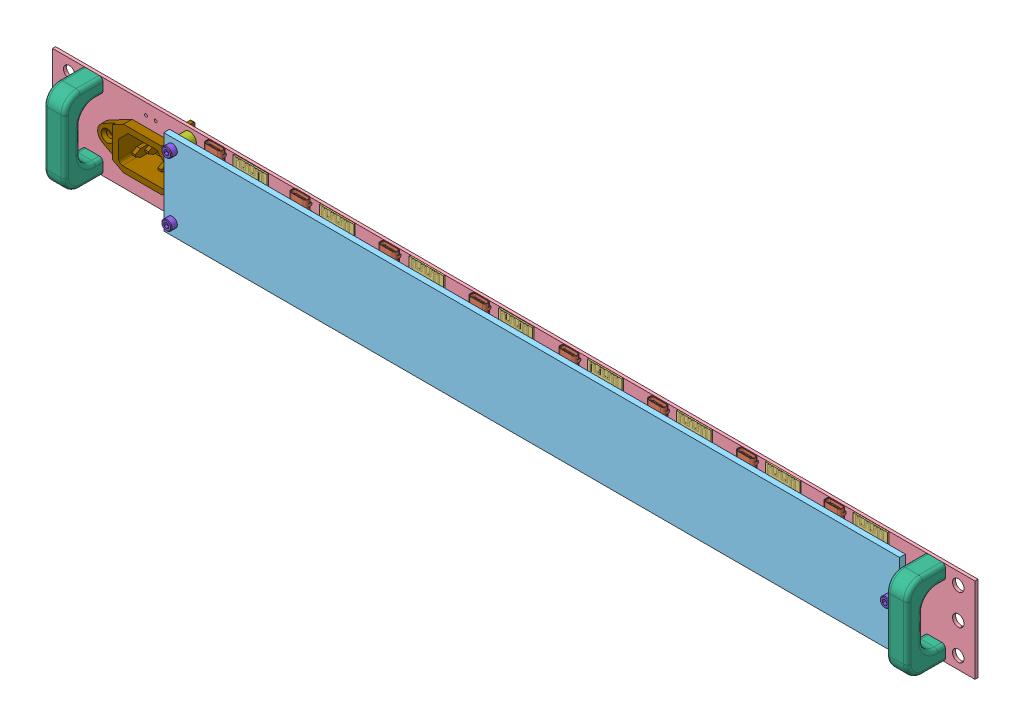
SolidWorks assembly RACK-ESP32S-SOLID, configuration Défaut. Lengths in mm.
Overall size (482.6 44.77 41.9).
68 component instances, 10 part files, 45 mates.
Components (placement in the parent):
- RACK-ESP32S-SOLID.step-1: RACK-ESP32S-SOLID.step [Défaut] at origin size (482.6 44.77 11.2)
  - OLED 128x32 Display.step-1: OLED 128x32 Display.step [Défaut] at (348.1175 -118.745 4.15) size (38 12 11.2)
    - COMPOUND.step-1: COMPOUND.step [Défaut] at origin size (38 12 11.2)
  - USB Type C Port (SMD Type).step-1: USB Type C Port (SMD Type).step [Défaut] at (304.165 -83.395 3.15) x (-1 0 0) z (0 0 -1) size (8.94 7.9 4.2)
    - COMPOUND-0.step-1: COMPOUND-0.step [Défaut] at origin size (8.94 7.9 4.2)
  - ESP32-S3-WROOM-1.step-1: ESP32-S3-WROOM-1.step [Défaut] at (406.16 -101.43 1.65) size (18 25.5 3.1)
    - COMPOUND-1.step-1: COMPOUND-1.step [Défaut] at origin size (18 25.5 3.1)
  - USB Type C Port (SMD Type).step-2: USB Type C Port (SMD Type).step [Défaut] at (397.129 -83.395 3.15) x (-1 0 0) z (0 0 -1) size (8.94 7.9 4.2)
    - COMPOUND-0.step-1: COMPOUND-0.step [Défaut] at origin size (8.94 7.9 4.2)
  - USB Type C Port (SMD Type).step-3: USB Type C Port (SMD Type).step [Défaut] at (350.52 -83.515 3.15) x (-1 0 0) z (0 0 -1) size (8.94 7.9 4.2)
    - COMPOUND-0.step-1: COMPOUND-0.step [Défaut] at origin size (8.94 7.9 4.2)
  - OLED 128x32 Display.step-2: OLED 128x32 Display.step [Défaut] at (440.8275 -118.745 4.15) size (38 12 11.2)
    - COMPOUND.step-1: COMPOUND.step [Défaut] at origin size (38 12 11.2)
  - OLED 128x32 Display.step-3: OLED 128x32 Display.step [Défaut] at (207.1475 -118.745 4.15) size (38 12 11.2)
    - COMPOUND.step-1: COMPOUND.step [Défaut] at origin size (38 12 11.2)
  - ESP32-S3-WROOM-1.step-2: ESP32-S3-WROOM-1.step [Défaut] at (359.745 -101.527 1.65) size (18 25.5 3.1)
    - COMPOUND-1.step-1: COMPOUND-1.step [Défaut] at origin size (18 25.5 3.1)
  - OLED 128x32 Display.step-4: OLED 128x32 Display.step [Défaut] at (254.7725 -118.745 4.15) size (38 12 11.2)
    - COMPOUND.step-1: COMPOUND.step [Défaut] at origin size (38 12 11.2)
  - ESP32-S3-WROOM-1.step-3: ESP32-S3-WROOM-1.step [Défaut] at (266.4 -101.745 1.65) size (18 25.5 3.1)
    - COMPOUND-1.step-1: COMPOUND-1.step [Défaut] at origin size (18 25.5 3.1)
  - ESP32-S3-WROOM-1.step-4: ESP32-S3-WROOM-1.step [Défaut] at (127.535 -101.748 1.65) size (18 25.5 3.1)
    - COMPOUND-1.step-1: COMPOUND-1.step [Défaut] at origin size (18 25.5 3.1)
  - USB Type C Port (SMD Type).step-4: USB Type C Port (SMD Type).step [Défaut] at (163.425 -83.145 3.15) x (-1 0 0) z (0 0 -1) size (8.94 7.9 4.2)
    - COMPOUND-0.step-1: COMPOUND-0.step [Défaut] at origin size (8.94 7.9 4.2)
  - OLED 128x32 Display.step-5: OLED 128x32 Display.step [Défaut] at (114.3 -118.745 4.15) size (38 12 11.2)
    - COMPOUND.step-1: COMPOUND.step [Défaut] at origin size (38 12 11.2)
  - USB Type C Port (SMD Type).step-5: USB Type C Port (SMD Type).step [Défaut] at (118.745 -83.268 3.15) x (-1 0 0) z (0 0 -1) size (8.94 7.9 4.2)
    - COMPOUND-0.step-1: COMPOUND-0.step [Défaut] at origin size (8.94 7.9 4.2)
  - ESP32-S3-WROOM-1.step-5: ESP32-S3-WROOM-1.step [Défaut] at (172.81 -101.595 1.65) size (18 25.5 3.1)
    - COMPOUND-1.step-1: COMPOUND-1.step [Défaut] at origin size (18 25.5 3.1)
  - ESP32-S3-WROOM-1.step-6: ESP32-S3-WROOM-1.step [Défaut] at (313.08 -101.525 1.65) size (18 25.5 3.1)
    - COMPOUND-1.step-1: COMPOUND-1.step [Défaut] at origin size (18 25.5 3.1)
  - USB Type C Port (SMD Type).step-6: USB Type C Port (SMD Type).step [Défaut] at (442.976 -83.395 3.15) x (-1 0 0) z (0 0 -1) size (8.94 7.9 4.2)
    - COMPOUND-0.step-1: COMPOUND-0.step [Défaut] at origin size (8.94 7.9 4.2)
  - USB Type C Port (SMD Type).step-7: USB Type C Port (SMD Type).step [Défaut] at (257.175 -83.295 3.15) x (-1 0 0) z (0 0 -1) size (8.94 7.9 4.2)
    - COMPOUND-0.step-1: COMPOUND-0.step [Défaut] at origin size (8.94 7.9 4.2)
  - ESP32-S3-WROOM-1.step-7: ESP32-S3-WROOM-1.step [Défaut] at (452.115 -101.595 1.65) size (18 25.5 3.1)
    - COMPOUND-1.step-1: COMPOUND-1.step [Défaut] at origin size (18 25.5 3.1)
  - ESP32-S3-WROOM-1.step-8: ESP32-S3-WROOM-1.step [Défaut] at (219.8 -101.455 1.65) size (18 25.5 3.1)
    - COMPOUND-1.step-1: COMPOUND-1.step [Défaut] at origin size (18 25.5 3.1)
  - USB Type C Port (SMD Type).step-8: USB Type C Port (SMD Type).step [Défaut] at (210.05 -83.325 3.15) x (-1 0 0) z (0 0 -1) size (8.94 7.9 4.2)
    - COMPOUND-0.step-1: COMPOUND-0.step [Défaut] at origin size (8.94 7.9 4.2)
  - OLED 128x32 Display.step-6: OLED 128x32 Display.step [Défaut] at (160.655 -118.745 4.15) size (38 12 11.2)
    - COMPOUND.step-1: COMPOUND.step [Défaut] at origin size (38 12 11.2)
  - OLED 128x32 Display.step-7: OLED 128x32 Display.step [Défaut] at (301.1275 -118.745 4.15) size (38 12 11.2)
    - COMPOUND.step-1: COMPOUND.step [Défaut] at origin size (38 12 11.2)
  - OLED 128x32 Display.step-8: OLED 128x32 Display.step [Défaut] at (394.4725 -118.745 4.15) size (38 12 11.2)
    - COMPOUND.step-1: COMPOUND.step [Défaut] at origin size (38 12 11.2)
  - RACK-ESP32S3 PCB.step-1: RACK-ESP32S3 PCB.step [Défaut] at origin size (482.6 44.6 1.6)
- vitre-1: vitre [Défaut] at (292.1466 -98.3103 7.65) size (385 44.6 3)
- poignee-1: poignee [Défaut] at (53.281 -98.2603 1.6) size (11 44.5 20)
- poignee-2: poignee [Défaut] at (494.089 -98.2603 1.6) size (11 44.5 20)
- spacers-1: spacers [Défaut] at (104.14 -114.3 1.6) size (7 7 6.05)
- spacers-2: spacers [Défaut] at (104.14 -81.28 1.6) size (7 7 6.05)
- spacers-3: spacers [Défaut] at (480.06 -97.155 1.6) size (7 7 6.05)
- socket head cap screw_ai-1: socket head cap screw_ai [HX-SHCS 0.125-44x0.188x0.188-N] at (104.14 -81.28 13.825) x (0 0 -1) z (1 0 0) size (7.95 5.21 5.21)
- socket head cap screw_ai-2: socket head cap screw_ai [HX-SHCS 0.125-44x0.188x0.188-N] at (104.14 -114.3 13.825) x (0 0 -1) z (1 0 0) size (7.95 5.21 5.21)
- socket head cap screw_ai-3: socket head cap screw_ai [HX-SHCS 0.125-44x0.188x0.188-N] at (480.06 -97.155 13.825) x (0 0 -1) z (1 0 0) size (7.95 5.21 5.21)
- IEC-C4-3pins-1: IEC-C4-3pins [Default] at (83.9847 -98.3103 4.6) size (50 22 26.4)
- oleddisplay-1: oleddisplay [Défaut] at (134.3 -112.795 6.65) size (26 11.6 0.1)
- oleddisplay-2: oleddisplay [Défaut] at (180.655 -112.795 6.65) size (26 11.6 0.1)
- oleddisplay-3: oleddisplay [Défaut] at (227.1475 -112.795 6.65) size (26 11.6 0.1)
- oleddisplay-4: oleddisplay [Défaut] at (274.7725 -112.795 6.65) size (26 11.6 0.1)
- oleddisplay-5: oleddisplay [Défaut] at (321.1275 -112.795 6.65) size (26 11.6 0.1)
- oleddisplay-6: oleddisplay [Défaut] at (368.1175 -112.795 6.65) size (26 11.6 0.1)
- oleddisplay-7: oleddisplay [Défaut] at (414.4725 -112.795 6.65) size (26 11.6 0.1)
- oleddisplay-8: oleddisplay [Défaut] at (460.8275 -112.795 6.65) size (26 11.6 0.1)
Mates (geometry in assembly coordinates):
- Coïncidente2: coincident aligned: plane of RACK-ESP32S-SOLID.step-1/RACK-ESP32S3 PCB.step-1 through (514.985 -120.6103 0) normal (0 -1 0); plane of vitre-1 through (99.6466 -120.6103 10.65) normal (0 -1 0)
- Coïncidente4: coincident anti-aligned: plane of vitre-1 through (292.1466 -98.3103 7.65) normal (0 0 -1)
- Coaxiale1: concentric aligned: cylinder of RACK-ESP32S-SOLID.step-1/RACK-ESP32S3 PCB.step-1 through (480.06 -97.155 -0.8) axis (0 0 1) radius 1.75; cylinder of vitre-1 through (480.06 -97.155 0.65) axis (0 0 1) radius 1.75
- Coïncidente5: coincident anti-aligned: plane of RACK-ESP32S-SOLID.step-1/RACK-ESP32S3 PCB.step-1 through (273.685 -98.3103 1.6) normal (0 0 1); plane of poignee-1 through (53.281 -98.2603 1.6) normal (0 0 -1)
- Coaxiale2: concentric anti-aligned: circle of RACK-ESP32S-SOLID.step-1/RACK-ESP32S3 PCB.step-1; circle of poignee-1
- Coïncidente7: coincident anti-aligned: plane of RACK-ESP32S-SOLID.step-1/RACK-ESP32S3 PCB.step-1 through (273.685 -98.3103 1.6) normal (0 0 1); plane of poignee-2 through (494.089 -98.2603 1.6) normal (0 0 -1)
- Coaxiale3: concentric anti-aligned: circle of RACK-ESP32S-SOLID.step-1/RACK-ESP32S3 PCB.step-1; circle of poignee-2
- Coïncidente9: coincident anti-aligned: plane of RACK-ESP32S-SOLID.step-1/RACK-ESP32S3 PCB.step-1 through (273.685 -98.3103 1.6) normal (0 0 1); plane of spacers-1 through (104.14 -114.3 1.6) normal (0 0 -1)
- Coaxiale4: concentric anti-aligned: cylinder of RACK-ESP32S-SOLID.step-1/RACK-ESP32S3 PCB.step-1 through (104.14 -114.3 -0.8) axis (0 0 1) radius 1.75; cylinder of spacers-1 through (104.14 -114.3 17.5495) axis (0 0 -1) radius 1.75
- Coïncidente10: coincident anti-aligned: plane of RACK-ESP32S-SOLID.step-1/RACK-ESP32S3 PCB.step-1 through (273.685 -98.3103 1.6) normal (0 0 1); plane of spacers-2 through (104.14 -81.28 1.6) normal (0 0 -1)
- Coïncidente11: coincident anti-aligned: circle of vitre-1; cylinder of spacers-2 through (104.14 -81.28 17.5495) axis (0 0 -1) radius 1.75
- Coïncidente12: coincident anti-aligned: plane of RACK-ESP32S-SOLID.step-1/RACK-ESP32S3 PCB.step-1 through (273.685 -98.3103 1.6) normal (0 0 1); plane of spacers-3 through (480.06 -97.155 1.6) normal (0 0 -1)
- Coaxiale5: concentric anti-aligned: circle of RACK-ESP32S-SOLID.step-1/RACK-ESP32S3 PCB.step-1; circle of spacers-3
- Coaxiale61: concentric aligned: cylinder of vitre-1 through (104.14 -81.28 0.65) axis (0 0 1) radius 1.75; cylinder of socket head cap screw_ai-1 through (104.14 -81.28 45.575) axis (0 0 1) radius 1.5875
- Coïncidente141: coincident anti-aligned: plane of vitre-1 through (292.1466 -98.3103 10.65) normal (0 0 1); plane of socket head cap screw_ai-1 through (104.14 -78.6765 10.65) normal (0 0 -1)
- Coaxiale71: concentric aligned: cylinder of vitre-1 through (104.14 -114.3 0.65) axis (0 0 1) radius 1.75; cylinder of socket head cap screw_ai-2 through (104.14 -114.3 45.575) axis (0 0 1) radius 1.5875
- Coïncidente151: coincident anti-aligned: plane of vitre-1 through (292.1466 -98.3103 10.65) normal (0 0 1); plane of socket head cap screw_ai-2 through (104.14 -111.6965 10.65) normal (0 0 -1)
- Coaxiale81: concentric aligned: cylinder of vitre-1 through (480.06 -97.155 0.65) axis (0 0 1) radius 1.75; cylinder of socket head cap screw_ai-3 through (480.06 -97.155 45.575) axis (0 0 1) radius 1.5875
- Coïncidente161: coincident anti-aligned: plane of vitre-1 through (292.1466 -98.3103 10.65) normal (0 0 1); plane of socket head cap screw_ai-3 through (480.06 -94.5515 10.65) normal (0 0 -1)
- Coïncidente17: coincident anti-aligned: plane of RACK-ESP32S-SOLID.step-1/RACK-ESP32S3 PCB.step-1 through (273.685 -98.3103 1.6) normal (0 0 1); plane of IEC-C4-3pins-1 through (83.9847 -98.3103 1.6) normal (0 0 -1)
- Coaxiale9: concentric anti-aligned: circle of RACK-ESP32S-SOLID.step-1/RACK-ESP32S3 PCB.step-1; circle of IEC-C4-3pins-1
- Coïncidente19: coincident anti-aligned: plane of RACK-ESP32S-SOLID.step-1/OLED 128x32 Display.step-5/COMPOUND.step-1 through (121.3 -118.595 6.65) normal (0 0 1); plane of oleddisplay-1 through (134.3 -112.795 6.65) normal (0 0 -1)
- Coïncidente20: coincident aligned: plane of RACK-ESP32S-SOLID.step-1/OLED 128x32 Display.step-5/COMPOUND.step-1 through (121.3 -118.595 5.65) normal (0 -1 0); plane of oleddisplay-1 through (121.3 -118.595 6.75) normal (0 -1 0)
- Coïncidente21: coincident: plane of RACK-ESP32S-SOLID.step-1/OLED 128x32 Display.step-5/COMPOUND.step-1 through (121.3 -118.595 5.65) normal (-1 0 0); line of oleddisplay-1 through (121.3 -106.995 6.65) axis (0 -1 0)
- Coïncidente22: coincident anti-aligned: plane of RACK-ESP32S-SOLID.step-1/OLED 128x32 Display.step-6/COMPOUND.step-1 through (167.655 -118.595 6.65) normal (0 0 1); plane of oleddisplay-2 through (180.655 -112.795 6.65) normal (0 0 -1)
- Coïncidente23: coincident aligned: plane of RACK-ESP32S-SOLID.step-1/OLED 128x32 Display.step-6/COMPOUND.step-1 through (167.655 -118.595 5.65) normal (0 -1 0); plane of oleddisplay-2 through (167.655 -118.595 6.75) normal (0 -1 0)
- Coïncidente24: coincident aligned: plane of RACK-ESP32S-SOLID.step-1/OLED 128x32 Display.step-6/COMPOUND.step-1 through (167.655 -118.595 5.65) normal (-1 0 0); plane of oleddisplay-2 through (167.655 -118.595 6.75) normal (-1 0 0)
- Coïncidente25: coincident anti-aligned: plane of RACK-ESP32S-SOLID.step-1/OLED 128x32 Display.step-3/COMPOUND.step-1 through (214.1475 -118.595 6.65) normal (0 0 1); plane of oleddisplay-3 through (227.1475 -112.795 6.65) normal (0 0 -1)
- Coïncidente26: coincident aligned: plane of RACK-ESP32S-SOLID.step-1/OLED 128x32 Display.step-3/COMPOUND.step-1 through (214.1475 -118.595 5.65) normal (0 -1 0); plane of oleddisplay-3 through (214.1475 -118.595 6.75) normal (0 -1 0)
- Coïncidente27: coincident aligned: plane of RACK-ESP32S-SOLID.step-1/OLED 128x32 Display.step-3/COMPOUND.step-1 through (214.1475 -118.595 5.65) normal (-1 0 0); plane of oleddisplay-3 through (214.1475 -118.595 6.75) normal (-1 0 0)
- Coïncidente28: coincident anti-aligned: plane of RACK-ESP32S-SOLID.step-1/OLED 128x32 Display.step-4/COMPOUND.step-1 through (261.7725 -118.595 6.65) normal (0 0 1); plane of oleddisplay-4 through (274.7725 -112.795 6.65) normal (0 0 -1)
- Coïncidente29: coincident aligned: plane of RACK-ESP32S-SOLID.step-1/OLED 128x32 Display.step-4/COMPOUND.step-1 through (261.7725 -118.595 5.65) normal (0 -1 0); plane of oleddisplay-4 through (261.7725 -118.595 6.75) normal (0 -1 0)
- Coïncidente30: coincident aligned: plane of RACK-ESP32S-SOLID.step-1/OLED 128x32 Display.step-4/COMPOUND.step-1 through (261.7725 -118.595 5.65) normal (-1 0 0); plane of oleddisplay-4 through (261.7725 -118.595 6.75) normal (-1 0 0)
- Coïncidente31: coincident anti-aligned: plane of RACK-ESP32S-SOLID.step-1/OLED 128x32 Display.step-7/COMPOUND.step-1 through (308.1275 -118.595 6.65) normal (0 0 1); plane of oleddisplay-5 through (321.1275 -112.795 6.65) normal (0 0 -1)
- Coïncidente32: coincident aligned: plane of RACK-ESP32S-SOLID.step-1/OLED 128x32 Display.step-7/COMPOUND.step-1 through (308.1275 -118.595 5.65) normal (0 -1 0); plane of oleddisplay-5 through (308.1275 -118.595 6.75) normal (0 -1 0)
- Coïncidente33: coincident aligned: plane of RACK-ESP32S-SOLID.step-1/OLED 128x32 Display.step-7/COMPOUND.step-1 through (308.1275 -118.595 5.65) normal (-1 0 0); plane of oleddisplay-5 through (308.1275 -118.595 6.75) normal (-1 0 0)
- Coïncidente34: coincident anti-aligned: plane of RACK-ESP32S-SOLID.step-1/OLED 128x32 Display.step-1/COMPOUND.step-1 through (355.1175 -118.595 6.65) normal (0 0 1); plane of oleddisplay-6 through (368.1175 -112.795 6.65) normal (0 0 -1)
- Coïncidente35: coincident aligned: plane of RACK-ESP32S-SOLID.step-1/OLED 128x32 Display.step-1/COMPOUND.step-1 through (355.1175 -118.595 5.65) normal (-1 0 0); plane of oleddisplay-6 through (355.1175 -118.595 6.75) normal (-1 0 0)
- Coïncidente36: coincident aligned: plane of RACK-ESP32S-SOLID.step-1/OLED 128x32 Display.step-1/COMPOUND.step-1 through (355.1175 -118.595 5.65) normal (0 -1 0); plane of oleddisplay-6 through (355.1175 -118.595 6.75) normal (0 -1 0)
- Coïncidente37: coincident anti-aligned: plane of RACK-ESP32S-SOLID.step-1/OLED 128x32 Display.step-8/COMPOUND.step-1 through (401.4725 -118.595 6.65) normal (0 0 1); plane of oleddisplay-7 through (414.4725 -112.795 6.65) normal (0 0 -1)
- Coïncidente38: coincident aligned: plane of RACK-ESP32S-SOLID.step-1/OLED 128x32 Display.step-8/COMPOUND.step-1 through (401.4725 -118.595 5.65) normal (0 -1 0); plane of oleddisplay-7 through (401.4725 -118.595 6.75) normal (0 -1 0)
- Coïncidente39: coincident aligned: plane of RACK-ESP32S-SOLID.step-1/OLED 128x32 Display.step-8/COMPOUND.step-1 through (401.4725 -118.595 5.65) normal (-1 0 0); plane of oleddisplay-7 through (401.4725 -118.595 6.75) normal (-1 0 0)
- Coïncidente40: coincident anti-aligned: plane of RACK-ESP32S-SOLID.step-1/OLED 128x32 Display.step-2/COMPOUND.step-1 through (447.8275 -118.595 6.65) normal (0 0 1); plane of oleddisplay-8 through (460.8275 -112.795 6.65) normal (0 0 -1)
- Coïncidente41: coincident aligned: plane of RACK-ESP32S-SOLID.step-1/OLED 128x32 Display.step-2/COMPOUND.step-1 through (447.8275 -118.595 5.65) normal (0 -1 0); plane of oleddisplay-8 through (447.8275 -118.595 6.75) normal (0 -1 0)
- Coïncidente42: coincident aligned: plane of RACK-ESP32S-SOLID.step-1/OLED 128x32 Display.step-2/COMPOUND.step-1 through (447.8275 -118.595 5.65) normal (-1 0 0); plane of oleddisplay-8 through (447.8275 -118.595 6.75) normal (-1 0 0)
